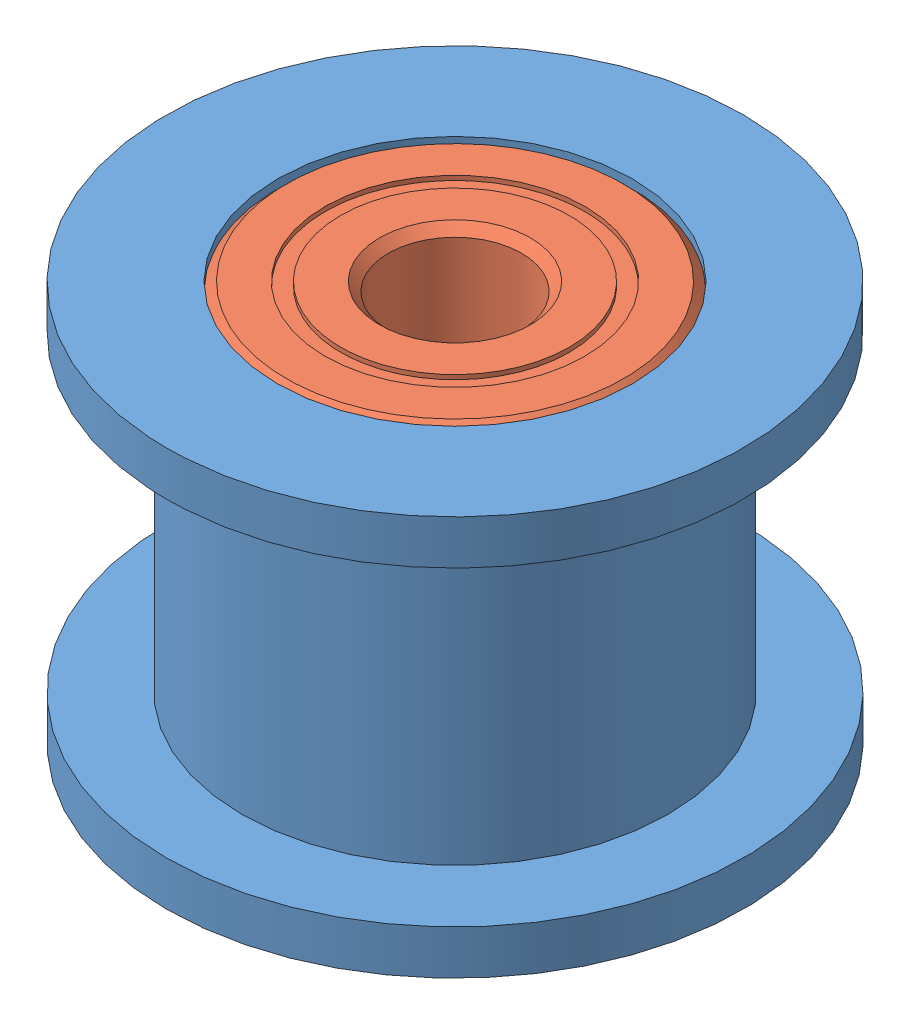
SolidWorks assembly 1021795, configuration Default. Lengths in mm.
Overall size (13 9 13).
3 component instances, 2 part files, 5 mates.
Components (placement in the parent):
- 1021795-IDLER PULLEY-1: 1021795-IDLER PULLEY [Default] at origin size (13 9 13)
- 1021795-693-2Z BEARING, 8 mm OD, 3 mm ID, 4 mm WIDTH-1: 1021795-693-2Z BEARING, 8 mm OD, 3 mm ID, 4 mm WIDTH [DEFAULT] at (0 2.5 0) x (-0.422593 0 0.90632) z (0 -1 0) size (8 8 4)
- 1021795-693-2Z BEARING, 8 mm OD, 3 mm ID, 4 mm WIDTH-2: 1021795-693-2Z BEARING, 8 mm OD, 3 mm ID, 4 mm WIDTH [DEFAULT] at (0 -2.5 0) x (0.989142 0 -0.14696) z (0 -1 0) size (8 8 4)
Mates (geometry in assembly coordinates):
- Coincident1: coordinate: point of 1021795-IDLER PULLEY-1; point of assembly
- Concentric1: concentric anti-aligned: cylinder of 1021795-IDLER PULLEY-1 through (0 -4.5 0) axis (0 1 0) radius 2; cylinder of 1021795-693-2Z BEARING, 8 mm OD, 3 mm ID, 4 mm WIDTH-1 through (0 0.5 0) axis (0 -1 0) radius 1.5
- Coincident2: coincident anti-aligned: plane of 1021795-IDLER PULLEY-1 through (0 0.5 0) normal (0 1 0); plane of 1021795-693-2Z BEARING, 8 mm OD, 3 mm ID, 4 mm WIDTH-1 through (-3.444 0.5 -1.6059) normal (0 -1 0)
- Concentric2: concentric anti-aligned: cylinder of 1021795-IDLER PULLEY-1 through (0 -4.5 0) axis (0 1 0) radius 2; cylinder of 1021795-693-2Z BEARING, 8 mm OD, 3 mm ID, 4 mm WIDTH-2 through (0 -4.5 0) axis (0 -1 0) radius 1.5
- Coincident3: coincident anti-aligned: plane of 1021795-IDLER PULLEY-1 through (0 -0.5 0) normal (0 -1 0); plane of 1021795-693-2Z BEARING, 8 mm OD, 3 mm ID, 4 mm WIDTH-2 through (0.5584 -0.5 3.7587) normal (0 1 0)
